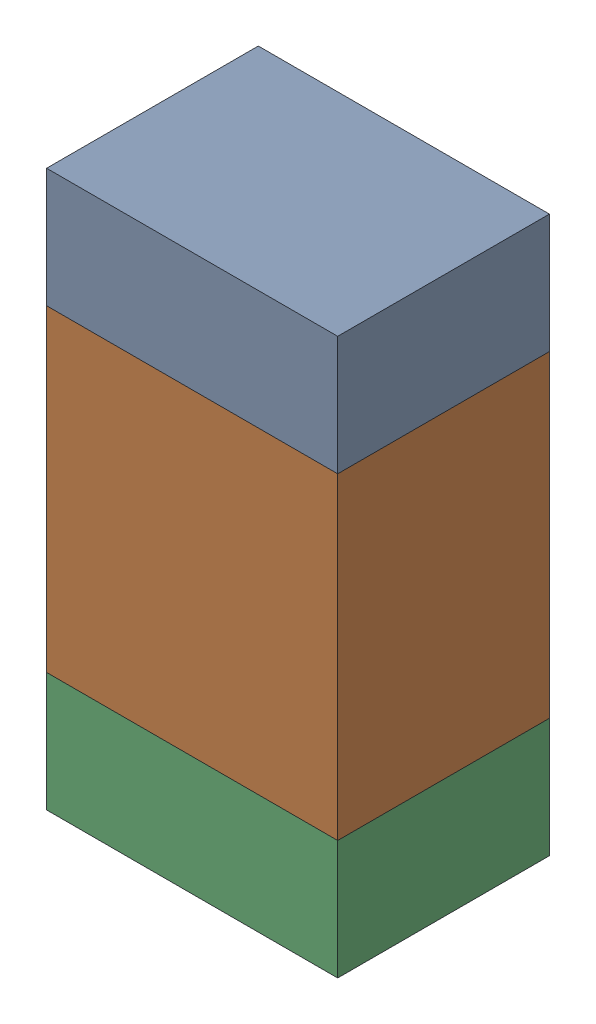
SolidWorks assembly R305_2PCB, configuration Default. Lengths in mm.
Overall size (0.55 1.05 0.4).
6 component instances, 2 part files, 0 mates.
Components (placement in the parent):
- 846483288-1: 846483288 [Default] at (139.5999 88.6126 0) size (0.55 0.22 0.4)
  - Extruded_12-1: Extruded_12 [Default] at origin size (0.55 0.22 0.4)
- 846483424-1: 846483424 [Default] at (139.5999 88.2001 0) size (0.55 0.6 0.4)
  - Extruded_13-1: Extruded_13 [Default] at origin size (0.55 0.6 0.4)
- 846483288-2: 846483288 [Default] at (139.5999 87.7876 0) size (0.55 0.22 0.4)
  - Extruded_12-1: Extruded_12 [Default] at origin size (0.55 0.22 0.4)
